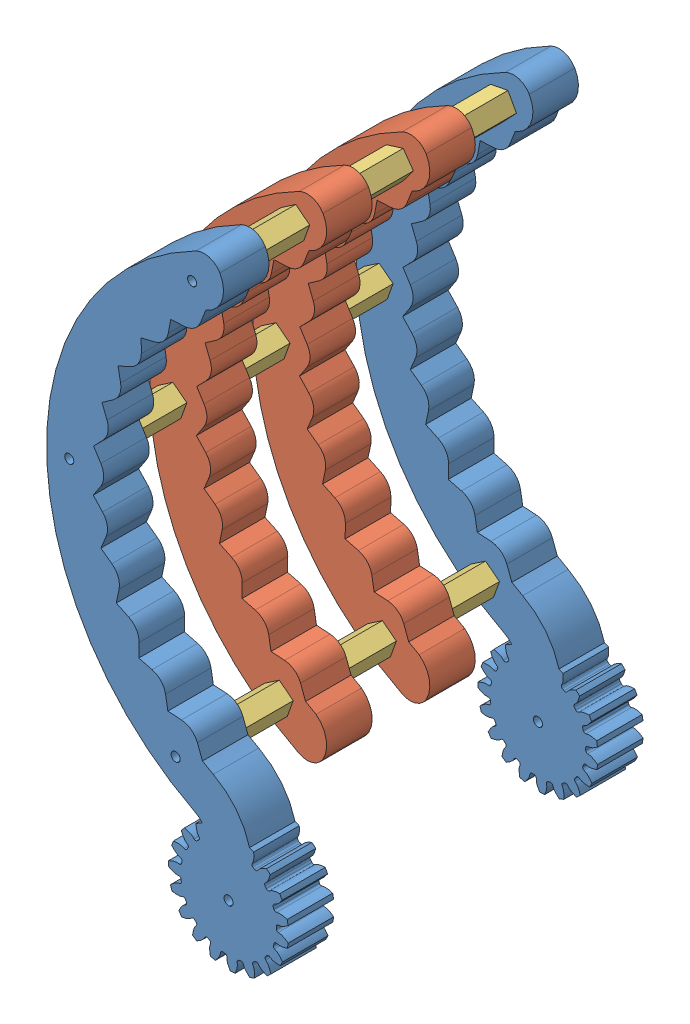
SolidWorks assembly 装配体_左爪子, configuration Default. Lengths in mm.
Overall size (79.66 200.49 117).
13 component instances, 3 part files, 27 mates.
Components (placement in the parent):
- 1_1.左爪子表面_打印两个-1: 1_1.左爪子表面_打印两个 [Varsayılan] at origin size (79.66 200.49 15)
- 1_3.爪子中间_打印四个-1: 1_3.爪子中间_打印四个 [Varsayılan] at (-3.003 8.3732 -34) size (58.35 161.77 15)
- 2.铜柱连接件-1: 2.铜柱连接件 [Varsayılan] at (-28.744 -59.1471 -21.5) x (0.366858 -0.930277 0) z (0 0 1) size (9.37 9.17 19)
- 2.铜柱连接件-2: 2.铜柱连接件 [Varsayılan] at (-63.8139 8.3557 -21.5) x (0.366858 -0.930277 0) z (0 0 1) size (9.37 9.17 19)
- 2.铜柱连接件-3: 2.铜柱连接件 [Varsayılan] at (-23.3149 79.364 -21.5) x (0.366858 -0.930277 0) z (0 0 1) size (9.37 9.17 19)
- 2.铜柱连接件-4: 2.铜柱连接件 [Varsayılan] at (-23.3149 79.364 -55.5) x (-0.923835 -0.38279 0) z (0 0 1) size (9.37 9.17 19)
- 2.铜柱连接件-5: 2.铜柱连接件 [Varsayılan] at (-63.8139 8.3557 -55.5) x (0.366858 -0.930277 0) z (0 0 1) size (9.37 9.17 19)
- 2.铜柱连接件-6: 2.铜柱连接件 [Varsayılan] at (-28.744 -59.1471 -55.5) x (0.366858 -0.930277 0) z (0 0 1) size (9.37 9.17 19)
- 2.铜柱连接件-7: 2.铜柱连接件 [Varsayılan] at (-28.744 -59.1471 -89.5) x (0.366858 -0.930277 0) z (0 0 1) size (9.37 9.17 19)
- 2.铜柱连接件-8: 2.铜柱连接件 [Varsayılan] at (-23.3149 79.364 -89.5) x (-0.960896 -0.276909 0) z (0 0 1) size (9.37 9.17 19)
- 2.铜柱连接件-9: 2.铜柱连接件 [Varsayılan] at (-63.8139 8.3557 -89.5) x (0.366858 -0.930277 0) z (0 0 1) size (9.37 9.17 19)
- 1_3.爪子中间_打印四个-2: 1_3.爪子中间_打印四个 [Varsayılan] at (-3.003 8.3732 -68) size (58.35 161.77 15)
- 1_1.左爪子表面_打印两个-2: 1_1.左爪子表面_打印两个 [Varsayılan] at (0 0 -102) size (79.66 200.49 15)
Mates (geometry in assembly coordinates):
- 同心1: concentric aligned: cylinder of 1_1.左爪子表面_打印两个-1 through (-28.744 -59.1471 -1) axis (0 0 -1) radius 1.5; cylinder of 2.铜柱连接件-1 through (-28.744 -59.1471 -2.5) axis (0 0 -1) radius 2.5
- 重合1: coincident anti-aligned: plane of 1_1.左爪子表面_打印两个-1 through (-26.1159 71.1438 -2.5) normal (0 0 -1); plane of 2.铜柱连接件-1 through (-28.744 -59.1471 -2.5) normal (0 0 1)
- 重合2: coincident anti-aligned: plane of 1_1.左爪子表面_打印两个-1 through (-26.1159 71.1438 -2.5) normal (0 0 -1); plane of 2.铜柱连接件-2 through (-63.8139 8.3557 -2.5) normal (0 0 1)
- 同心2: concentric anti-aligned: cylinder of 1_1.左爪子表面_打印两个-1 through (-63.8139 8.3557 -1) axis (0 0 -1) radius 1.5; circle of 2.铜柱连接件-2
- 同心3: concentric aligned: cylinder of 1_1.左爪子表面_打印两个-1 through (-23.3149 79.364 -1) axis (0 0 -1) radius 1.5; cylinder of 2.铜柱连接件-3 through (-23.3149 79.364 -2.5) axis (0 0 -1) radius 2.5
- 重合3: coincident anti-aligned: plane of 1_1.左爪子表面_打印两个-1 through (-26.1159 71.1438 -2.5) normal (0 0 -1); plane of 2.铜柱连接件-3 through (-23.3149 79.364 -2.5) normal (0 0 1)
- 重合4: coincident anti-aligned: plane of 1_3.爪子中间_打印四个-1 through (-26.1159 71.1438 -21.5) normal (0 0 1); plane of 2.铜柱连接件-3 through (-23.3149 79.364 -21.5) normal (0 0 -1)
- 同心4: concentric aligned: cylinder of 1_3.爪子中间_打印四个-1 through (-23.3149 79.364 -35) axis (0 0 -1) radius 1.5; cylinder of 2.铜柱连接件-3 through (-23.3149 79.364 -2.5) axis (0 0 -1) radius 2.5
- 同心5: concentric aligned: cylinder of 1_3.爪子中间_打印四个-1 through (-63.8139 8.3557 -35) axis (0 0 -1) radius 1.5; cylinder of 2.铜柱连接件-2 through (-63.8139 8.3557 -2.5) axis (0 0 -1) radius 2.5
- 同心6: concentric aligned: cylinder of 1_3.爪子中间_打印四个-1 through (-23.3149 79.364 -35) axis (0 0 -1) radius 1.5; cylinder of 2.铜柱连接件-4 through (-23.3149 79.364 -36.5) axis (0 0 -1) radius 2.5
- 重合5: coincident anti-aligned: plane of 1_3.爪子中间_打印四个-1 through (-26.1159 71.1438 -36.5) normal (0 0 -1); plane of 2.铜柱连接件-4 through (-23.3149 79.364 -36.5) normal (0 0 1)
- 重合6: coincident aligned: point of 1_3.爪子中间_打印四个-1; moEndPointRef_w of 2.铜柱连接件-5
- 同心7: concentric aligned: cylinder of 1_3.爪子中间_打印四个-1 through (-63.8139 8.3557 -35) axis (0 0 -1) radius 1.5; cylinder of 2.铜柱连接件-5 through (-63.8139 8.3557 -36.5) axis (0 0 -1) radius 2.5
- 同心8: concentric aligned: cylinder of 1_3.爪子中间_打印四个-1 through (-28.744 -59.1471 -35) axis (0 0 -1) radius 1.5; cylinder of 2.铜柱连接件-6 through (-28.744 -59.1471 -36.5) axis (0 0 -1) radius 2.5
- 重合7: coincident: plane of 1_3.爪子中间_打印四个-1 through (-26.1159 71.1438 -36.5) normal (0 0 -1); point of 2.铜柱连接件-6
- 同心9: concentric aligned: circle of 2.铜柱连接件-4; circle of 1_3.爪子中间_打印四个-2
- 重合8: coincident anti-aligned: plane of 2.铜柱连接件-4 through (-23.3149 79.364 -55.5) normal (0 0 -1); plane of 1_3.爪子中间_打印四个-2 through (-26.1159 71.1438 -55.5) normal (0 0 1)
- 同心10: concentric aligned: circle of 2.铜柱连接件-5; circle of 1_3.爪子中间_打印四个-2
- 同心11: concentric anti-aligned: circle of 2.铜柱连接件-8; cylinder of 1_3.爪子中间_打印四个-2 through (-23.3149 79.364 -69) axis (0 0 -1) radius 1.5
- 重合9: coincident anti-aligned: plane of 2.铜柱连接件-8 through (-23.3149 79.364 -70.5) normal (0 0 1); plane of 1_3.爪子中间_打印四个-2 through (-26.1159 71.1438 -70.5) normal (0 0 -1)
- 重合10: coincident anti-aligned: plane of 2.铜柱连接件-9 through (-63.8139 8.3557 -70.5) normal (0 0 1); plane of 1_3.爪子中间_打印四个-2 through (-26.1159 71.1438 -70.5) normal (0 0 -1)
- 同心12: concentric aligned: circle of 2.铜柱连接件-9; circle of 1_3.爪子中间_打印四个-2
- 重合11: coincident anti-aligned: plane of 2.铜柱连接件-7 through (-28.744 -59.1471 -70.5) normal (0 0 1); plane of 1_3.爪子中间_打印四个-2 through (-26.1159 71.1438 -70.5) normal (0 0 -1)
- 同心13: concentric anti-aligned: cylinder of 2.铜柱连接件-7 through (-28.744 -59.1471 -70.5) axis (0 0 -1) radius 2.5; circle of 1_3.爪子中间_打印四个-2
- 重合12: coincident anti-aligned: plane of 2.铜柱连接件-8 through (-23.3149 79.364 -89.5) normal (0 0 -1); plane of 1_1.左爪子表面_打印两个-2 through (-26.1159 71.1438 -89.5) normal (0 0 1)
- 同心14: concentric aligned: cylinder of 2.铜柱连接件-8 through (-23.3149 79.364 -70.5) axis (0 0 -1) radius 2.5; cylinder of 1_1.左爪子表面_打印两个-2 through (-23.3149 79.364 -103) axis (0 0 -1) radius 1.5
- 同心15: concentric anti-aligned: cylinder of 2.铜柱连接件-9 through (-63.8139 8.3557 -70.5) axis (0 0 -1) radius 2.5; circle of 1_1.左爪子表面_打印两个-2
